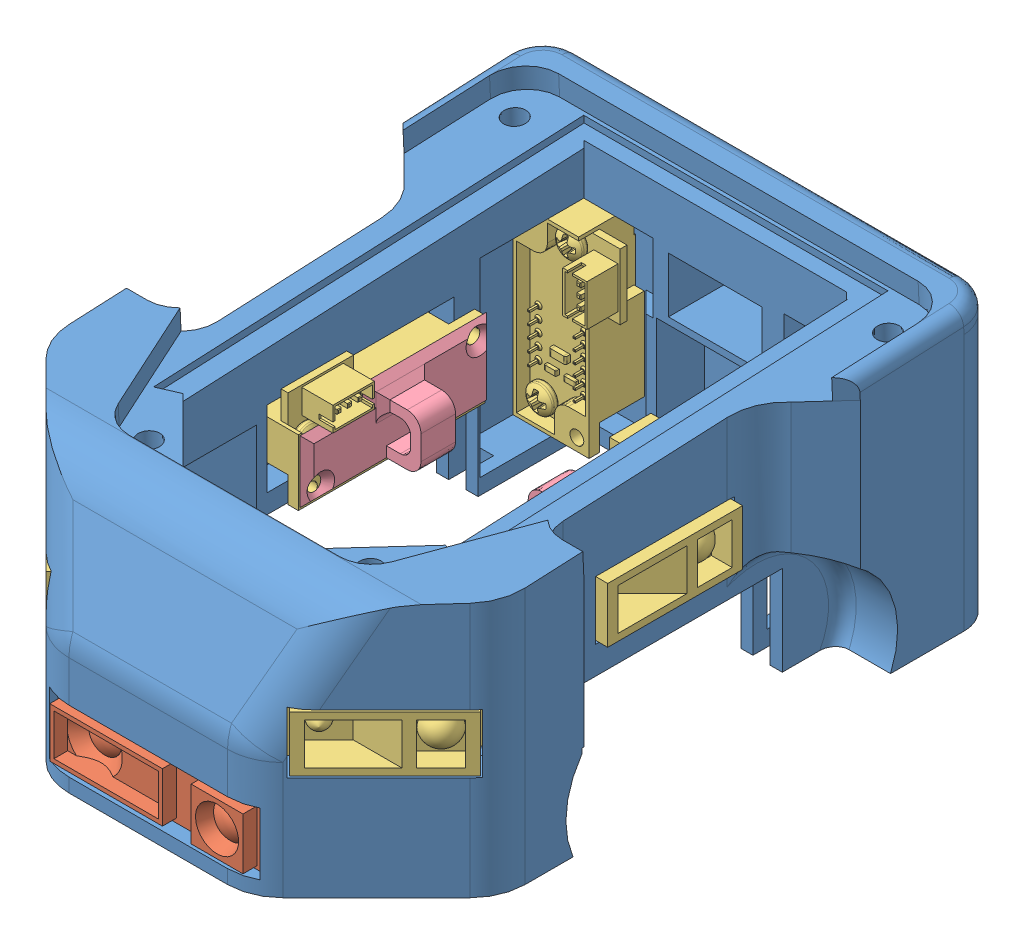
SolidWorks assembly CumCamBien, configuration Default. Lengths in mm.
Overall size (68.12 38.28 90.3).
13 component instances, 5 part files, 36 mates.
Components (placement in the parent):
- GaCamBien-1: GaCamBien [Default] at (44.4541 29.6514 59.1279) x (-1 0 0) z (0 0 -1) size (66.02 38.28 90.01)
- GP2Y0A41SK0F-1: GP2Y0A41SK0F [Default] at (44.4541 36.1514 98.9279) x (-1 0 0) z (0 0 1) size (29.5 18.9 13.5)
- SHARP GP2Y0A51SK0F-1: SHARP GP2Y0A51SK0F [Default] at (47.2766 33.231 61.8028) x (0 0 1) z (0 1 0) size (27 14.5 13.5)
- SHARP GP2Y0A51SK0F-2: SHARP GP2Y0A51SK0F [Default] at (45.5336 45.0334 52.4505) x (0 1 0) z (1 0 0) size (27 14.5 13.5)
- SHARP GP2Y0A51SK0F-3: SHARP GP2Y0A51SK0F [Default] at (8.0336 45.0334 52.4505) x (0 1 0) z (1 0 0) size (27 14.5 13.5)
- SHARP GP2Y0A51SK0F-4: SHARP GP2Y0A51SK0F [Default] at (41.6316 33.231 63.0389) x (0 0 -1) z (0 1 0) size (27 14.5 13.5)
- SHARP GP2Y0A51SK0F-5: SHARP GP2Y0A51SK0F [Default] at (40.2365 31.231 81.2349) x (0.707107 0 0.707107) z (0 1 0) size (27 14.5 13.5)
- SHARP GP2Y0A51SK0F-6: SHARP GP2Y0A51SK0F [Default] at (47.7976 31.231 82.109) x (0.707107 0 -0.707107) z (0 1 0) size (27 14.5 13.5)
- op sensor v2-1: op sensor v2 [Default] at (29.9541 51.1514 62.1708) x (0 0 1) z (1 0 0) size (27 11 6.5)
- op sensor v2-2: op sensor v2 [Default] at (58.9541 51.1514 62.6708) x (0 0 -1) z (-1 0 0) size (27 11 6.5)
- op sensor v2-3: op sensor v2 [Default] at (28.2479 49.1514 93.7441) x (0.707107 0 0.707107) z (0.707107 0 -0.707107) size (27 11 6.5)
- op sensor v2-4: op sensor v2 [Default] at (60.3068 49.1514 94.0976) x (0.707107 0 -0.707107) z (-0.707107 0 -0.707107) size (27 11 6.5)
- Part2-1: Part2 [Default] at (44.4541 36.1514 99.2279) x (1 0 0) z (0 -1 0) size (28 7.44 17)
Mates (geometry in assembly coordinates):
- Width1: width anti-aligned: plane of GP2Y0A41SK0F-1 through (59.2041 31.9514 98.9279) normal (1 0 0); plane of GaCamBien-1 through (29.7041 40.3514 98.9279) normal (-1 0 0); plane of GP2Y0A41SK0F-1 through (59.7041 40.6514 119.1279) normal (-1 0 0); plane of GaCamBien-1 through (29.2041 40.6514 119.1279) normal (1 0 0)
- Width2: width anti-aligned: plane of GP2Y0A41SK0F-1 through (59.2041 40.3514 98.9279) normal (0 1 0); plane of GaCamBien-1 through (29.7041 31.9514 98.9279) normal (0 -1 0); plane of GP2Y0A41SK0F-1 through (29.2041 40.6514 119.1279) normal (0 -1 0); plane of GaCamBien-1 through (29.2041 31.6514 119.1279) normal (0 1 0)
- Width3: width anti-aligned: plane of GaCamBien-1 through (61.5442 53.1514 80.8394) normal (-0.707107 0 0.707107); plane of SHARP GP2Y0A51SK0F-6 through (47.4021 53.1514 94.9815) normal (0.707107 0 -0.707107); plane of GaCamBien-1 through (75.8631 44.9014 95.5118) normal (0.707107 0 -0.707107); plane of SHARP GP2Y0A51SK0F-6 through (62.0745 52.9014 109.3004) normal (-0.707107 0 0.707107)
- Width4: width anti-aligned: plane of SHARP GP2Y0A51SK0F-6 through (75.8631 52.9014 95.5118) normal (0 1 0); plane of GaCamBien-1 through (62.0745 44.9014 109.3004) normal (0 -1 0); plane of SHARP GP2Y0A51SK0F-6 through (47.4021 53.1514 94.9815) normal (0 -1 0); plane of GaCamBien-1 through (47.4021 44.6514 94.9815) normal (0 1 0)
- Width5: width aligned: plane of SHARP GP2Y0A51SK0F-5 through (26.8337 52.9014 109.3004) normal (0 1 0); plane of GaCamBien-1 through (13.0451 44.9014 95.5118) normal (0 -1 0); plane of SHARP GP2Y0A51SK0F-5 through (41.5061 44.6514 94.9815) normal (0 1 0); plane of GaCamBien-1 through (41.5061 53.1514 94.9815) normal (0 -1 0)
- Width6: width anti-aligned: plane of SHARP GP2Y0A51SK0F-5 through (26.8337 44.9014 109.3004) normal (0.707107 0 0.707107); plane of GaCamBien-1 through (13.0451 52.9014 95.5118) normal (-0.707107 0 -0.707107); plane of SHARP GP2Y0A51SK0F-5 through (41.5061 53.1514 94.9815) normal (-0.707107 0 -0.707107); plane of GaCamBien-1 through (27.364 53.1514 80.8394) normal (0.707107 0 0.707107)
- Width7: width anti-aligned: plane of SHARP GP2Y0A51SK0F-4 through (70.9541 46.9014 52.6708) normal (0 0 -1); plane of GaCamBien-1 through (70.9541 54.9014 72.1708) normal (0 0 1); plane of SHARP GP2Y0A51SK0F-4 through (79.4541 55.1514 52.4208) normal (0 0 1); plane of GaCamBien-1 through (79.4541 55.1514 72.4208) normal (0 0 -1)
- Width8: width aligned: plane of SHARP GP2Y0A51SK0F-4 through (70.9541 54.9014 52.6708) normal (0 1 0); plane of GaCamBien-1 through (70.9541 46.9014 72.1708) normal (0 -1 0); plane of SHARP GP2Y0A51SK0F-4 through (79.4541 46.6514 72.4208) normal (0 1 0); plane of GaCamBien-1 through (79.4541 55.1514 72.4208) normal (0 -1 0)
- Width9: width anti-aligned: plane of SHARP GP2Y0A51SK0F-1 through (17.9541 54.9014 72.1708) normal (0 1 0); plane of GaCamBien-1 through (17.9541 46.9014 52.6708) normal (0 -1 0); plane of SHARP GP2Y0A51SK0F-1 through (79.4541 55.1514 72.4208) normal (0 -1 0); plane of GaCamBien-1 through (79.4541 46.6514 72.4208) normal (0 1 0)
- Width10: width anti-aligned: plane of SHARP GP2Y0A51SK0F-1 through (17.9541 46.9014 72.1708) normal (0 0 1); plane of GaCamBien-1 through (17.9541 54.9014 52.6708) normal (0 0 -1); plane of SHARP GP2Y0A51SK0F-1 through (79.4541 55.1514 72.4208) normal (0 0 -1); plane of GaCamBien-1 through (79.4541 55.1514 52.4208) normal (0 0 1)
- Width11: width anti-aligned: plane of SHARP GP2Y0A51SK0F-3 through (21.7041 55.4014 23.1279) normal (0 1 0); plane of GaCamBien-1 through (29.7041 35.9014 23.1279) normal (0 -1 0); plane of SHARP GP2Y0A51SK0F-3 through (-24.8156 55.6514 36.134) normal (0 -1 0); plane of GaCamBien-1 through (-24.8156 35.6514 36.134) normal (0 1 0)
- Width12: width anti-aligned: plane of SHARP GP2Y0A51SK0F-3 through (21.7041 35.9014 23.1279) normal (-1 0 0); plane of GaCamBien-1 through (29.7041 55.4014 23.1279) normal (1 0 0); plane of SHARP GP2Y0A51SK0F-3 through (21.4541 64.6514 36.134) normal (1 0 0); plane of GaCamBien-1 through (29.9541 64.6514 36.134) normal (-1 0 0)
- Width13: width anti-aligned: plane of SHARP GP2Y0A51SK0F-2 through (59.2041 35.9014 23.1279) normal (-1 0 0); plane of GaCamBien-1 through (67.2041 55.4014 23.1279) normal (1 0 0); plane of SHARP GP2Y0A51SK0F-2 through (58.9541 64.6514 36.134) normal (1 0 0); plane of GaCamBien-1 through (67.4541 64.6514 36.134) normal (-1 0 0)
- Width14: width anti-aligned: plane of GaCamBien-1 through (-24.8156 35.6514 36.134) normal (0 1 0); plane of SHARP GP2Y0A51SK0F-2 through (-24.8156 55.6514 36.134) normal (0 -1 0); plane of GaCamBien-1 through (67.2041 35.9014 23.1279) normal (0 -1 0); plane of SHARP GP2Y0A51SK0F-2 through (59.2041 55.4014 23.1279) normal (0 1 0)
- Coincident1: coincident aligned: plane of SHARP GP2Y0A51SK0F-2 through (63.2041 45.6514 23.1279) normal (0 0 -1); plane of SHARP GP2Y0A51SK0F-3 through (25.7041 45.6514 23.1279) normal (0 0 -1)
- Coincident2: coincident anti-aligned: plane of GaCamBien-1 through (44.4541 29.6514 27.1279) normal (0 0 1); plane of SHARP GP2Y0A51SK0F-2 through (63.2041 45.6514 27.1279) normal (0 0 -1)
- Coincident3: coincident anti-aligned: plane of GaCamBien-1 through (66.9541 29.6514 59.1279) normal (-1 0 0); plane of SHARP GP2Y0A51SK0F-4 through (66.9541 50.9014 62.4208) normal (1 0 0)
- Coincident4: coincident anti-aligned: plane of GaCamBien-1 through (21.9541 29.6514 59.1279) normal (1 0 0); plane of SHARP GP2Y0A51SK0F-1 through (21.9541 50.9014 62.4208) normal (-1 0 0)
- Coincident5: coincident anti-aligned: plane of GaCamBien-1 through (75.5221 29.6514 90.196) normal (-0.707107 0 -0.707107); plane of SHARP GP2Y0A51SK0F-6 through (66.1404 48.9014 99.5777) normal (0.707107 0 0.707107)
- Coincident6: coincident anti-aligned: plane of GaCamBien-1 through (13.3861 29.6514 90.196) normal (0.707107 0 -0.707107); plane of SHARP GP2Y0A51SK0F-5 through (22.7678 48.9014 99.5777) normal (-0.707107 0 0.707107)
- Coincident7: coincident anti-aligned: plane of GaCamBien-1 through (44.4541 29.6514 106.1279) normal (0 0 -1); plane of GP2Y0A41SK0F-1 through (44.4541 30.8014 106.1279) normal (0 0 1)
- Coincident8: coincident aligned: cylinder of SHARP GP2Y0A51SK0F-1 through (17.9541 54.6514 50.6708) axis (1 0 0) radius 1; circle of op sensor v2-1
- Parallel1: parallel anti-aligned: line of SHARP GP2Y0A51SK0F-1 through (29.9541 56.4014 65.9208) axis (0 0 -1); line of op sensor v2-1 through (29.9541 56.6514 48.6708) axis (0 0 1)
- Coincident11: coincident anti-aligned: plane of SHARP GP2Y0A51SK0F-1 through (29.9541 50.9014 62.4208) normal (1 0 0); plane of op sensor v2-1 through (29.9541 51.1514 62.1708) normal (-1 0 0)
- Coincident12: coincident aligned: cylinder of SHARP GP2Y0A51SK0F-4 through (70.9541 54.6514 74.1708) axis (-1 0 0) radius 1; circle of op sensor v2-2
- Parallel2: parallel anti-aligned: line of SHARP GP2Y0A51SK0F-4 through (58.9541 56.4014 58.9208) axis (0 0 1); line of op sensor v2-2 through (58.9541 56.6514 76.1708) axis (0 0 -1)
- Coincident14: coincident anti-aligned: plane of SHARP GP2Y0A51SK0F-4 through (58.9541 50.9014 62.4208) normal (-1 0 0); plane of op sensor v2-2 through (58.9541 51.1514 62.6708) normal (1 0 0)
- Coincident15: coincident aligned: cylinder of SHARP GP2Y0A51SK0F-6 through (60.6603 52.6514 110.7146) axis (-0.707107 0 -0.707107) radius 1; circle of op sensor v2-4
- Parallel3: parallel anti-aligned: line of SHARP GP2Y0A51SK0F-6 through (62.9584 54.4014 91.446) axis (-0.707107 0 0.707107); line of op sensor v2-4 through (50.7608 54.6514 103.6436) axis (0.707107 0 -0.707107)
- Coincident17: coincident anti-aligned: plane of SHARP GP2Y0A51SK0F-6 through (60.4835 48.9014 93.9208) normal (-0.707107 0 -0.707107); plane of op sensor v2-4 through (60.3068 49.1514 94.0976) normal (0.707107 0 0.707107)
- Coincident18: coincident aligned: cylinder of SHARP GP2Y0A51SK0F-5 through (11.6309 52.6514 94.0976) axis (0.707107 0 -0.707107) radius 1; circle of op sensor v2-3
- Parallel4: parallel anti-aligned: line of SHARP GP2Y0A51SK0F-5 through (30.8995 54.4014 96.3957) axis (-0.707107 0 -0.707107); line of op sensor v2-3 through (18.7019 54.6514 84.1981) axis (0.707107 0 0.707107)
- Coincident20: coincident anti-aligned: plane of SHARP GP2Y0A51SK0F-5 through (28.4247 48.9014 93.9208) normal (0.707107 0 -0.707107); plane of op sensor v2-3 through (28.2479 49.1514 93.7441) normal (-0.707107 0 0.707107)
- Width15: width anti-aligned: plane of Part2-1 through (44.4541 41.6514 101.2279) normal (0 1 0); plane of GP2Y0A41SK0F-1 through (44.4541 30.6514 101.2279) normal (0 -1 0); plane of Part2-1 through (49.9541 42.1514 102.2279) normal (0 -1 0); plane of GP2Y0A41SK0F-1 through (30.3682 30.1514 102.2279) normal (0 1 0)
- Width16: width anti-aligned: plane of Part2-1 through (39.4541 36.1514 101.2279) normal (-1 0 0); plane of GP2Y0A41SK0F-1 through (49.4541 36.1514 101.2279) normal (1 0 0); plane of Part2-1 through (38.9541 43.1514 102.2279) normal (1 0 0); plane of GP2Y0A41SK0F-1 through (49.9541 43.1514 102.2279) normal (-1 0 0)
- Distance1: distance = 1 mm anti-aligned: plane of GP2Y0A41SK0F-1 through (49.5041 40.3514 102.2279) normal (0 0 -1); plane of Part2-1 through (44.4541 36.1514 101.2279) normal (0 0 1)
